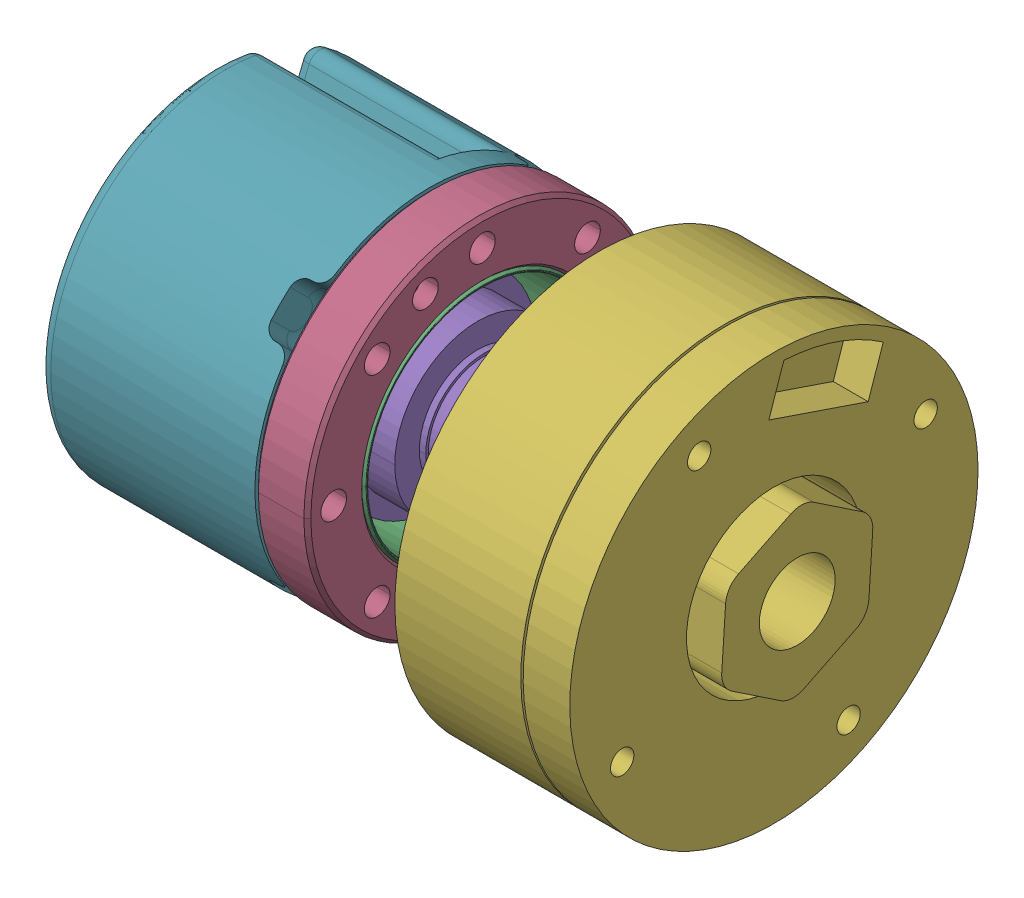
SolidWorks assembly TransmissionExampleSmall, configuration Default. Lengths in mm.
Overall size (52 46.86 46.86).
4 component instances, 4 part files, 11 mates.
Components (placement in the parent):
- CSF-8-XXX-2A-R-1: CSF-8-XXX-2A-R [Default] at (-21.3986 3.5645 3.0391) size (22.1 30 30)
- GM2804-1: GM2804 [Default] at (5.6014 3.5645 3.0391) x (0 0.441664 -0.897181) z (0 -0.897181 -0.441664) size (35 17 35)
- CSF-8-output-1-1: CSF-8-output-1 [Default] at (-8.8986 3.5645 3.0391) x (0 -0.70614 -0.708072) z (0 0.708072 -0.70614) size (30 18.1 30)
- CSF-8-output-2-1: CSF-8-output-2 [Default] at (-29.3986 3.5645 3.0391) x (0 0 -1) z (0 -1 0) size (20 9.5 20)
Mates (geometry in assembly coordinates):
- Concentric1: concentric aligned: cone of CSF-8-XXX-2A-R-1 through (-18.2374 3.5645 3.0391) axis (-1 0 0); cylinder of CSF-8-Bracket-1 through (-12.6986 3.5645 3.0391) axis (-1 0 0) radius 6
- Coincident1: coincident anti-aligned: plane of CSF-8-XXX-2A-R-1 through (-18.6986 -5.748 3.0391) normal (1 0 0); plane of CSF-8-Bracket-1 through (-18.6986 3.5645 3.0391) normal (-1 0 0)
- Parallel2: parallel anti-aligned: plane of CSF-8-XXX-2A-R-1 through (-19.8986 0.9665 1.5391) normal (0 0 1); plane of CSF-8-output-1 through (-48.1669 -2.6403 1.6891) normal (0 0 -1)
- Concentric3: concentric aligned: cylinder of CSF-8-XXX-2A-R-1 through (-11.2986 3.5645 3.0391) axis (-1 0 0) radius 3.5; cylinder of GM2804-1 through (22.6024 3.5645 3.0391) axis (-1 0 0) radius 3.25
- Distance1: distance = 10 mm anti-aligned: plane of GM2804-1 through (5.6014 3.5645 3.0391) normal (-1 0 0); plane of CSF-8-XXX-2A-R-1 through (-4.3986 18.5645 3.0391) normal (1 0 0)
- Concentric4: concentric aligned: cylinder of CSF-8-XXX-2A-R-1 through (-32.9764 3.5645 3.0391) axis (-1 0 0) radius 3; cylinder of CSF-8-output-1 through (-48.1669 3.5645 3.0391) axis (-1 0 0) radius 2.7
- Concentric5: concentric anti-aligned: cylinder of CSF-8-XXX-2A-R-1 through (-49.7879 3.5645 3.0391) axis (-1 0 0) radius 15; cylinder of CSF-8-output-1-1 through (-26.8986 3.5645 3.0391) axis (1 0 0) radius 15
- Coincident8: coincident anti-aligned: plane of CSF-8-XXX-2A-R-1 through (-8.8986 18.5645 3.0391) normal (-1 0 0); plane of CSF-8-output-1-1 through (-8.8986 3.5645 3.0391) normal (1 0 0)
- Concentric6: concentric aligned: cylinder of CSF-8-XXX-2A-R-1 through (-32.9764 3.5645 3.0391) axis (-1 0 0) radius 3; cylinder of CSF-8-output-2-1 through (-19.8986 3.5645 3.0391) axis (-1 0 0) radius 2.7
- Parallel3: parallel anti-aligned: plane of CSF-8-XXX-2A-R-1 through (-19.8986 0.9665 1.5391) normal (0 0 1); plane of CSF-8-output-2-1 through (-19.8986 1.2263 1.6891) normal (0 0 -1)
- Coincident9: coincident anti-aligned: plane of CSF-8-XXX-2A-R-1 through (-21.3986 0.5645 3.0391) normal (-1 0 0); plane of CSF-8-output-2-1 through (-21.3986 3.5645 3.0391) normal (1 0 0)
